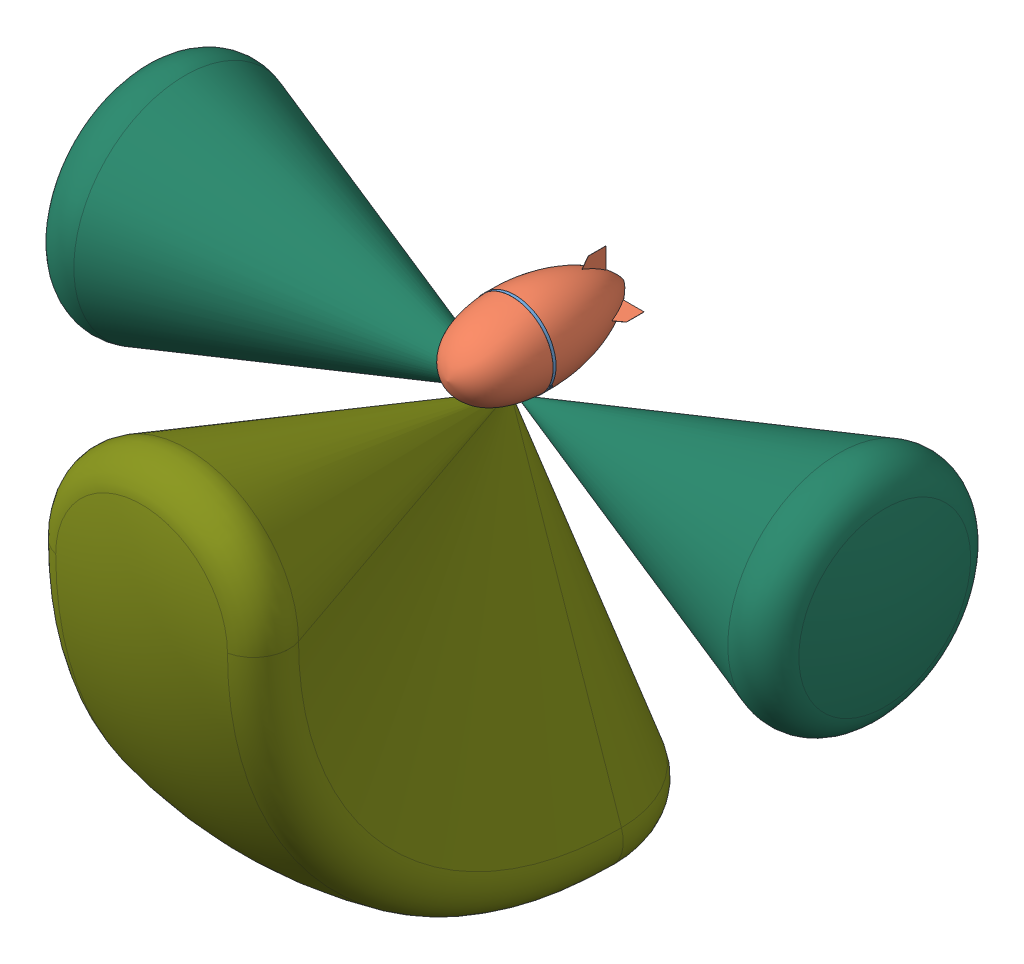
SolidWorks assembly BLIMP_sonar, configuration Default. Lengths in mm.
Overall size (13040 8377.22 8407.22).
26 component instances, 16 part files, 18 mates.
Components (placement in the parent):
- COPOLING_RING-1: COPOLING_RING [Default] at origin size (1402 1402 50)
  - estrutura de acopolamento-1: estrutura de acopolamento [Default] at origin size (1402 1402 50)
- envelope-1: envelope [Default] at (0 0 1100) size (1876.01 1876.01 3000)
- GONDOLA-1: GONDOLA [Default] at (0 -700 70) size (139.38 110.34 205.99)
  - gondola-1: gondola [Default] at origin size (139.38 85.01 205.99)
  - Towerpro mg16r-1: Towerpro mg16r [Default] at (-49.3349 -85.5863 -106.4276) x (0 0 -1) z (0 -1 0) size (33 30 12)
  - perno monobraco servo-1: perno monobraco servo [Default] at (-23.3349 -77 -105.8) x (0 0.120221 -0.992747) z (0 -0.992747 -0.120221) size (41 5.7 8)
  - apoio_camera-1: apoio_camera [Default] at (-17.6349 -59.5495 -83.5406) x (1 0 0) z (0 -0.120221 0.992747) size (30 50 40)
  - LV-EZ0-1: LV-EZ0 [Default] at (-4.2742 -97.0513 -90.4971) x (1 0 0) z (0 0.992747 0.120221) size (19.9 16.44 22.1)
    - LV-EZ0_4-1: LV-EZ0_4 [Default] at (1.6393 -0.3975 -0.4339) size (19.9 1.25 22.1)
    - LV-EZ0_1-1: LV-EZ0_1 [Default] at (-8.2207 0.2775 6.3761) size (1.5 1.15 1.5)
    - LV-EZ0_2-1: LV-EZ0_2 [Default] at (-8.2207 0.2775 8.9161) size (1.5 1.15 1.5)
    - LV-EZ0_3-1: LV-EZ0_3 [Default] at (-4.6707 0.2775 -8.9339) size (4 1.15 4)
    - LV-EZ0_5-1: LV-EZ0_5 [Default] at (1.6393 -0.8975 -0.4339) x (1 0 0) z (0 0 -1) size (15.5 15.81 15.5)
    - LV-EZ0_6-1: LV-EZ0_6 [Default] at (1.6393 0.2275 -0.4339) x (-1 0 0) z (0 0 1) size (11 5 11)
    - LV-EZ0_7-1: LV-EZ0_7 [Default] at (1.6393 -3.7725 -0.4339) x (-1 0 0) z (0 0 1) size (8.56 2.06 8.56)
    - LV-EZ0_1-3: LV-EZ0_1 [Default] at (-8.2207 0.2775 3.8361) size (1.5 1.15 1.5)
    - LV-EZ0_1-5: LV-EZ0_1 [Default] at (-8.2207 0.2775 1.2961) size (1.5 1.15 1.5)
    - LV-EZ0_1-7: LV-EZ0_1 [Default] at (-8.2207 0.2775 -1.2439) size (1.5 1.15 1.5)
    - LV-EZ0_1-9: LV-EZ0_1 [Default] at (-8.2207 0.2775 -3.7839) size (1.5 1.15 1.5)
    - LV-EZ0_3-3: LV-EZ0_3 [Default] at (7.9293 0.2775 8.0661) size (4 1.15 4)
    - LV-EZ0_1-13: LV-EZ0_1 [Default] at (-8.2207 0.2775 -6.3239) size (1.5 1.15 1.5)
  - camera-1: camera [Default] at (-2.6349 -72.2767 -103.2134) x (0 -0.992747 -0.120221) z (0 -0.120221 0.992747) size (21 26 23)
- cone_sonar-1: cone_sonar [Default] at (70 -715 0) size (6450 3854.44 3854.44)
- cone_sonar-2: cone_sonar [Default] at (-70 -715 0) x (-1 0 0) z (0 0 -1) size (6450 3854.44 3854.44)
- cone_sonar2-1: cone_sonar2 [Default] at (0 -673.1529 30) size (3854.44 8377.22 8377.22)
Mates (geometry in assembly coordinates):
- Coincident1: coincident aligned: plane of envelope-1 through (0 0 1100) normal (0 1 0); plane of assembly
- Coincident2: coincident aligned: plane of envelope-1 through (0 0 1100) normal (1 0 0); plane of assembly
- Coincident3: coincident aligned: plane of COPOLING_RING-1/estrutura de acopolamento-1 through (0 0 0) normal (0 1 0)
- Coincident4: coincident aligned: plane of COPOLING_RING-1/estrutura de acopolamento-1 through (0 0 0) normal (1 0 0)
- Distance1: distance = 1100 mm aligned: plane of assembly; plane of envelope-1 through (0 0 1100) normal (0 0 1)
- Coincident6: coincident aligned: plane of COPOLING_RING-1/estrutura de acopolamento-1 through (0 0 0) normal (0 0 1)
- Distance2: distance = 70 mm aligned: plane of GONDOLA-1/gondola-1 through (0 -700 70) normal (0 0 1)
- Coincident10: coincident aligned: plane of GONDOLA-1/gondola-1 through (0 -700 70) normal (1 0 0)
- Distance3: distance = 700 mm aligned: plane of GONDOLA-1/gondola-1 through (0 -700 70) normal (0 1 0)
- Distance4: distance = 30 mm aligned: plane of cone_sonar2-1 through (0 -673.1529 30) normal (0 0 1); plane of assembly
- Distance5: distance = 673.1529 mm aligned: plane of cone_sonar2-1 through (0 -673.1529 30) normal (0 1 0); plane of assembly
- Coincident13: coincident aligned: plane of cone_sonar2-1 through (0 -673.1529 30) normal (1 0 0); plane of assembly
- Distance6: distance = 70 mm aligned: plane of cone_sonar-1 through (70 -715 0) normal (1 0 0); plane of assembly
- Distance7: distance = 70 mm anti-aligned: plane of assembly; plane of cone_sonar-2 through (-70 -715 0) normal (-1 0 0)
- Distance8: distance = 715 mm aligned: plane of assembly; plane of cone_sonar-1 through (70 -715 0) normal (0 1 0)
- Distance9: distance = 715 mm aligned: plane of assembly; plane of cone_sonar-2
- Coincident19: coincident aligned: plane of cone_sonar-1 through (70 -715 0) normal (0 0 1); plane of assembly
- Coincident20: coincident anti-aligned: plane of cone_sonar-2 through (-70 -715 0) normal (0 0 -1); plane of assembly
